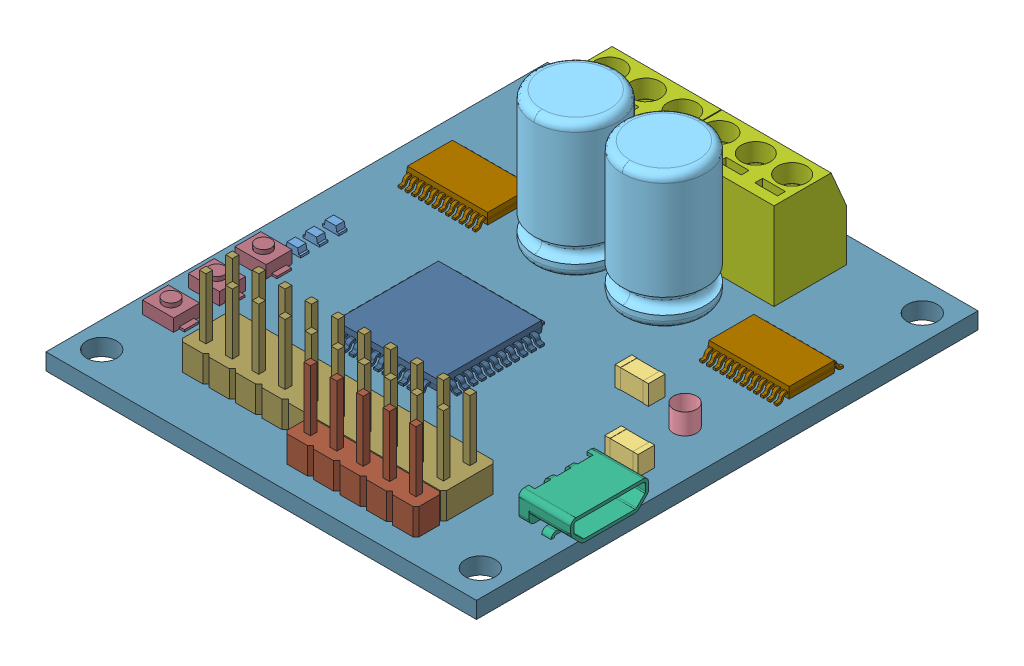
SolidWorks assembly Roboclaw, configuration Default. Lengths in mm.
Overall size (41.97 16.45 48.28).
26 component instances, 14 part files, 0 mates.
Components (placement in the parent):
- 404-1004-1-ND-4: 404-1004-1-ND [Default] at (73.9119 39.5455 59.9969) size (1.6 0.7 0.8)
- 404-1004-1-ND-5: 404-1004-1-ND [Default] at (73.9119 39.5455 61.8654) size (1.6 0.7 0.8)
- 404-1004-1-ND-6: 404-1004-1-ND [Default] at (73.9119 39.5455 63.6743) size (1.6 0.7 0.8)
- DB2W40200LCT-ND-3: DB2W40200LCT-ND [Default] at (76.3453 37.9455 73.6091) x (0 0 1) z (1 0 0) size (3.5 0.8 1.6)
- DB2W40200LCT-ND-4: DB2W40200LCT-ND [Default] at (74.2192 37.9455 73.6091) x (0 0 1) z (1 0 0) size (3.5 0.8 1.6)
- 587-3248-1-ND-3: 587-3248-1-ND [Default] at (102.2216 40.4955 58.909) x (0 0 -1) z (1 0 0) size (1.6 1.9 3.2)
- 587-3248-1-ND-4: 587-3248-1-ND [Default] at (107.6317 40.4955 65.3191) x (0 0 -1) z (1 0 0) size (1.6 1.9 3.2)
- SRN5040-220MCT-ND-2: SRN5040-220MCT-ND [Default] at (105.6664 42.9455 62.8284) x (-1 0 0) z (0 0 1) size (2.21 2 2.21)
- P15369TB-ND-3: P15369TB-ND [Default] at (95.395 39.5455 49.7941) x (-1 0 0) z (0 0 -1) size (8 16 8)
- 609-4618-1-ND-2: 609-4618-1-ND [Default] at (112.2359 40.9455 71.8547) x (0 0 -1) z (1 0 0) size (7.5 3.05 5)
- ED2636-ND-3: ED2636-ND [Default] at (85.709 39.5455 41.8431) x (-1 0 0) z (0 0 -1) size (10.5 11.85 7)
- IRF7351TRPBFCT-ND-5: IRF7351TRPBFCT-ND [Default] at (76.1828 37.6966 49.2664) x (-1 0 0) z (0 0 1) size (5 1.75 6.2)
- IRF7351TRPBFCT-ND-6: IRF7351TRPBFCT-ND [Default] at (81.9001 37.6966 49.2664) x (-1 0 0) z (0 0 1) size (5 1.75 6.2)
- IRF7351TRPBFCT-ND-7: IRF7351TRPBFCT-ND [Default] at (99.7733 37.6966 49.2664) x (-1 0 0) z (0 0 1) size (5 1.75 6.2)
- IRF7351TRPBFCT-ND-8: IRF7351TRPBFCT-ND [Default] at (105.4543 37.6966 49.2664) x (-1 0 0) z (0 0 1) size (5 1.75 6.2)
- 620-1319-1-ND-3: 620-1319-1-ND [Default] at (106.2731 39.6955 50.308) size (7.8 1.2 6.4)
- 620-1319-1-ND-4: 620-1319-1-ND [Default] at (77.2465 39.6955 50.308) size (7.8 1.2 6.4)
- ATXMEGA32A4U-AU-ND-2: ATXMEGA32A4U-AU-ND [Default] at (87.74 39.7455 63.8454) x (0 0 -1) z (1 0 0) size (12 1.2 12)
- PBC05SAAN-2: PBC05SAAN [Default] at (92.2279 39.5455 80.6492) size (12.7 11.43 2.54)
- PBC10DAAN-2: PBC10DAAN [Default] at (79.5294 39.5455 76.739) size (25.4 11.43 5.08)
- SW1020CT-ND-4: SW1020CT-ND [Default] at (73.2925 39.5455 66.2406) x (-1 0 0) z (0 0 -1) size (4 1.6 2.5)
- SW1020CT-ND-5: SW1020CT-ND [Default] at (73.2925 39.5455 70.7286) x (-1 0 0) z (0 0 -1) size (4 1.6 2.5)
- SW1020CT-ND-6: SW1020CT-ND [Default] at (73.2925 39.5455 75.1362) x (-1 0 0) z (0 0 -1) size (4 1.6 2.5)
- P15369TB-ND-4: P15369TB-ND [Default] at (86.9008 39.5455 49.7923) x (-1 0 0) z (0 0 -1) size (8 16 8)
- ED2636-ND-4: ED2636-ND [Default] at (96.2918 39.5455 41.8431) x (-1 0 0) z (0 0 -1) size (10.5 11.85 7)
- MC5A-PCB-2: MC5A-PCB [Default] at (90.9892 37.9455 60.0095) size (41.44 1.6 48.28)
